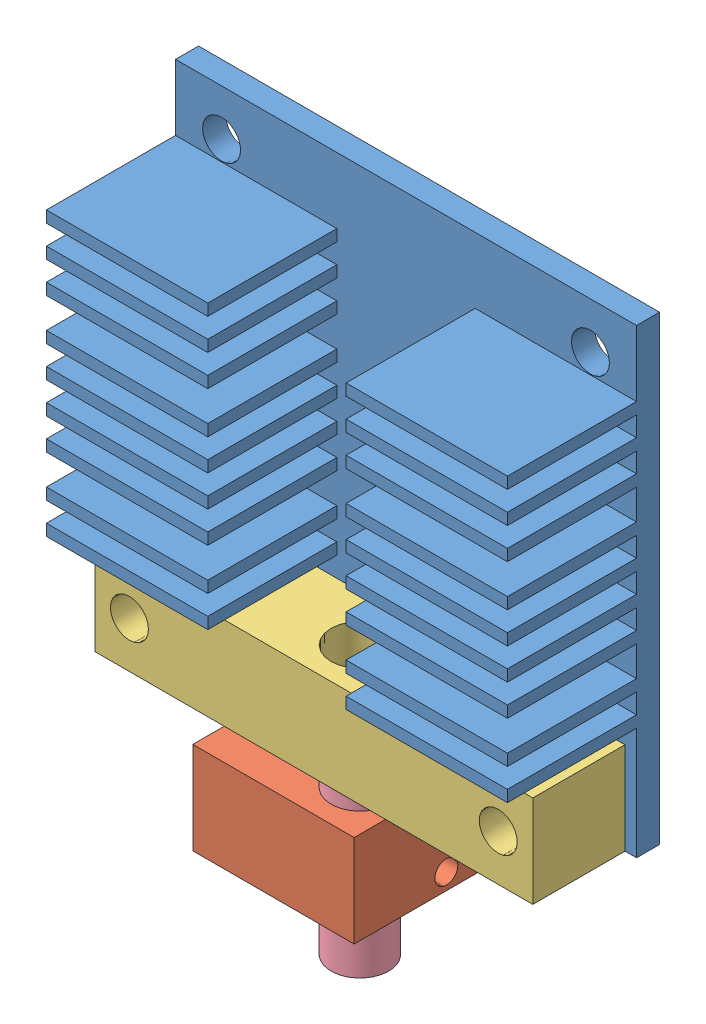
SolidWorks assembly extruer, configuration Default. Lengths in mm.
Overall size (40 56.44 19.2).
6 component instances, 6 part files, 13 mates.
Components (placement in the parent):
- extruder_adapter-2: extruder_adapter [Default] at (57.0941 60.6969 33.7712) x (-1 0 0) z (0 0 1) (suppressed, hidden)
- extruder_cap-1: extruder_cap [Default] at (5.5112 38.9154 68.7712) (suppressed, hidden)
- heat_sink-1: heat_sink [Default] at (57.0941 60.6969 43.0712) x (-1 0 0) z (0 0 1) size (40 40 13.2)
- nozzle_cube-1: nozzle_cube [Default] at (210.1229 7.4879 -311.713) x (0 0 1) z (-1 0 0) size (16 8 14)
- Part3-1: Part3 [Default] at (15.0941 -16.2705 45.0712)
- nozzle_05-1: nozzle_05 [Default] at (-331.4673 2.9763 65.7791) x (0.880687 0 -0.4737) z (0.4737 0 0.880687) size (5 20 5)
Mates (geometry in assembly coordinates):
- Coincident2: coincident aligned: plane of extruder_adapter-2 through (57.0941 60.6969 38.9712) normal (0 0 -1); plane of extruder_cap-1 through (5.5112 38.9154 38.9712) normal (0 0 -1)
- Coincident5: coincident aligned: plane of extruder_adapter-2 through (57.0941 59.9132 43.0712) normal (0 1 0); plane of extruder_cap-1 through (65.5941 59.9132 38.9712) normal (0 1 0)
- Coincident7: coincident anti-aligned: plane of extruder_adapter-2 through (57.0941 60.6969 43.0712) normal (0 0 1); plane of heat_sink-1 through (57.0941 60.6969 43.0712) normal (0 0 -1)
- Concentric1: concentric aligned: circle of extruder_adapter-2; circle of heat_sink-1
- Coincident8: coincident: plane of heat_sink-1 through (57.0941 60.6969 45.0712) normal (0 0 1); plane of Part3-1 through (15.0941 -16.2705 45.0712) normal (0 0 -1)
- Concentric2: concentric: circle of heat_sink-1; circle of Part3-1
- Concentric3: concentric: circle of nozzle_cube-1; circle of Part3-1
- Concentric4: concentric aligned: circle of extruder_adapter-2; circle of heat_sink-1
- Concentric5: concentric: circle of heat_sink-1; circle of Part3-1
- Concentric6: concentric aligned: circle of nozzle_cube-1; cylinder of nozzle_05-1 through (36.0941 1.7763 49.0712) axis (0 1 0) radius 2.5
- Distance1: distance = 5.7116 mm aligned: plane of nozzle_05-1 through (-331.4673 1.7763 65.7791) normal (0 -1 0); plane of nozzle_cube-1 through (210.1229 7.4879 -311.713) normal (0 -1 0)
- Distance2: distance = 2.7253 mm: plane of nozzle_cube-1 through (210.1229 15.4879 -311.713) normal (0 1 0); plane of Part3-1 through (55.0941 18.2132 53.0712) normal (0 -1 0)
- Parallel2: parallel: plane of nozzle_cube-1 through (25.5941 15.4879 37.0712) normal (0 0 -1); plane of Part3-1 through (15.0941 -16.2705 45.0712) normal (0 0 -1)
